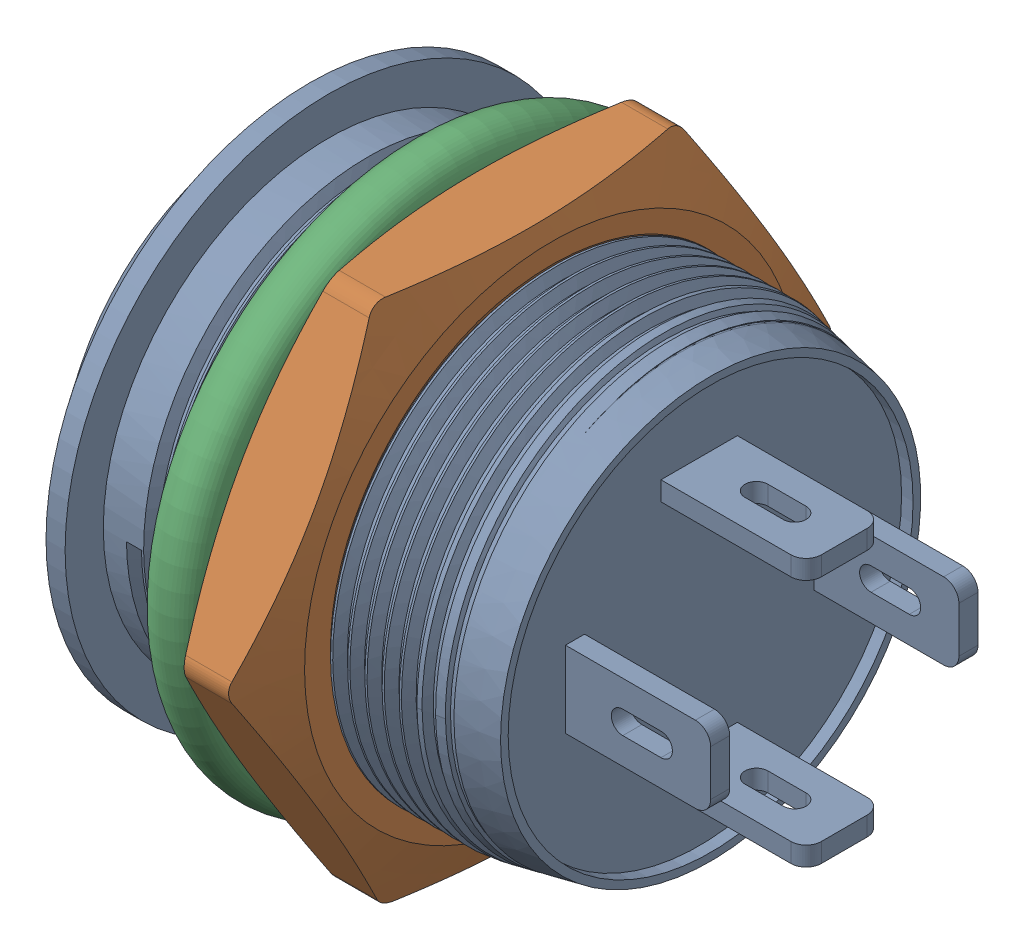
SolidWorks assembly Push_btn_asm, configuration По умолчанию. Lengths in mm.
Overall size (15.2 20.63 19.95).
3 component instances, 3 part files, 3 mates.
Components (placement in the parent):
- Push_btn-1: Push_btn [По умолчанию] at origin size (15.2 13.8 13.8)
- Push_btn_nut-1: Push_btn_nut [По умолчанию] at (6.3869 0 0) x (0 -0.513678 0.857983) z (0 0.857983 0.513678) size (13.8 2.61 15.78)
- Sealing_ring-1: Sealing_ring [По умолчанию] at (4.5369 0 0) x (0 0.94412 -0.329601) z (0 -0.329601 -0.94412) size (14.6 1.4 14.6)
Mates (geometry in assembly coordinates):
- Совпадение1: coincident anti-aligned: line of Push_btn-1 through (-0.76 0 0) axis (1 0 0); line of Гайка_кнопки-1 through (13.8487 0 0) axis (-1 0 0)
- Совпадение2: coincident anti-aligned: line of Push_btn-1 through (-0.76 0 0) axis (1 0 0); line of Уплотнительное кольцо-1 through (5.3619 0 0) axis (-1 0 0)
- Касательность1: tangent anti-aligned: plane of Гайка_кнопки-1 through (5.2369 0 0) normal (-1 0 0); torus of Уплотнительное кольцо-1
